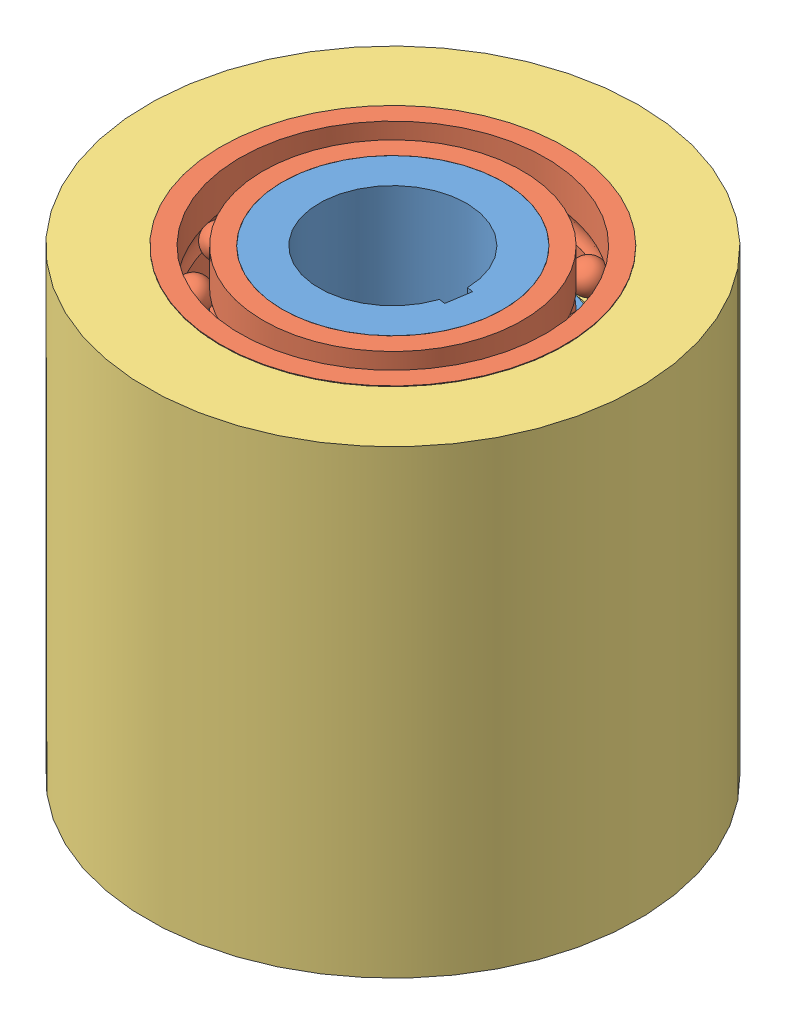
SolidWorks assembly one way bearing, configuration Default. Lengths in mm.
Overall size (82.54 75.1 82.54).
4 component instances, 3 part files, 6 mates.
Components (placement in the parent):
- inner race final-1: inner race final [Default] at (27.3509 36.7185 -30.5035) size (50 75 50.74)
- ball bearing-7: ball bearing [Default] at (30.9905 98.5403 12.8822) x (0 -1 0) z (-0.999857 0 0.016919) size (15 56 56)
- ball bearing-8: ball bearing [Default] at (30.9905 38.5403 12.8822) x (0 -1 0) z (-0.399103 0 0.916906) size (15 56 56)
- outer race final-2: outer race final [Default] at (30.0206 68.4419 -17.1022) x (0 1 0) z (0.999477 0 -0.032332) size (75 80 80)
Mates (geometry in assembly coordinates):
- Concentric16: concentric anti-aligned: cylinder of inner race final-1 through (30.9905 106.0403 12.8822) axis (0 -1 0) radius 18; cylinder of ball bearing-7 through (30.9905 1098.5403 12.8822) axis (0 1 0) radius 18
- Coincident7: coincident aligned: circle of inner race final-1; circle of ball bearing-7
- Concentric17: concentric anti-aligned: cylinder of inner race final-1 through (30.9905 106.0403 12.8822) axis (0 -1 0) radius 18; cylinder of ball bearing-8 through (30.9905 1038.5403 12.8822) axis (0 1 0) radius 18
- Coincident8: coincident aligned: circle of inner race final-1; circle of ball bearing-8
- Concentric19: concentric anti-aligned: cylinder of ball bearing-8 through (30.9905 1038.5403 12.8822) axis (0 1 0) radius 28; cylinder of outer race final-2 through (30.9905 -931.5581 12.8822) axis (0 -1 0) radius 28
- Concentric21: concentric anti-aligned: cylinder of ball bearing-7 through (30.9905 1098.5403 12.8822) axis (0 1 0) radius 28; cylinder of outer race final-2 through (30.9905 -931.5581 12.8822) axis (0 -1 0) radius 28
